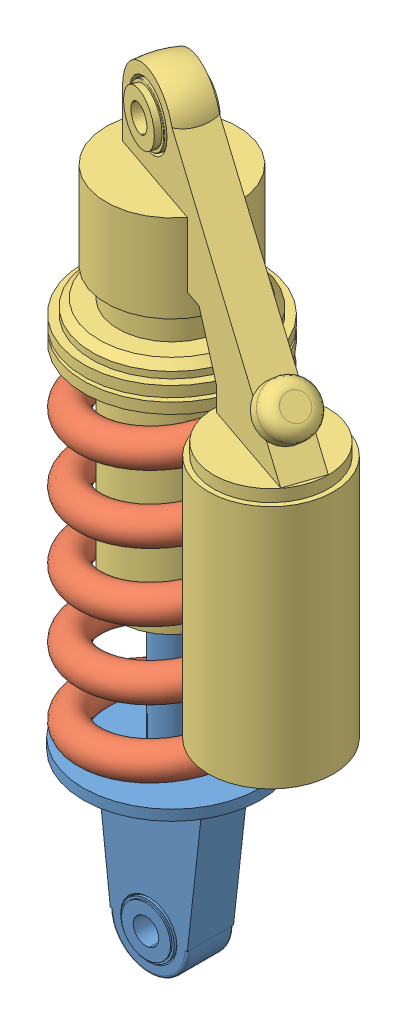
SolidWorks assembly SpringDamper, configuration Default. Lengths in mm.
Overall size (141.02 309.87 107.24).
3 component instances, 3 part files, 4 mates.
Components (placement in the parent):
- ShockInner-1: ShockInner [Default] at origin size (69 147.91 69)
- Spring68x12-2: Spring68x12 [CompressedRear300lbs1000ppi] at (0 54.45 0) x (-0.907984 0 -0.419005) z (0.419005 0 -0.907984) size (71.86 196.48 68.78)
- ShockOuter-1: ShockOuter [Default] at (0 272.38 0) x (0.94609 0 0.323905) z (-0.323905 0 0.94609) size (120.65 200.72 68.6)
Mates (geometry in assembly coordinates):
- Concentric1: concentric: cylinder of assembly; line of assembly; cylinder of ShockInner-1 through (0 0 0) axis (0 -1 0) radius 7; line of Spring68x12-2 through (190.4021 0 54.45) axis (0 0 1)
- Coincident4: coincident: line of assembly; line of Spring68x12-2 through (190.4021 0 54.45) axis (0 0 1); line of ShockOuter-1 through (185.1413 0 109.73) axis (0 0 1)
- Coincident5: coincident: plane of assembly; plane of assembly; plane of Spring68x12-2 through (0 193.43 0) normal (0 1 0); plane of ShockOuter-1 through (-32.4509 193.43 -11.1099) normal (0 -1 0)
- Coincident6: coincident: plane of assembly; plane of assembly; plane of ShockInner-1 through (34.5 60.45 0) normal (0 1 0); plane of Spring68x12-2 through (0 60.45 0) normal (0 -1 0)
